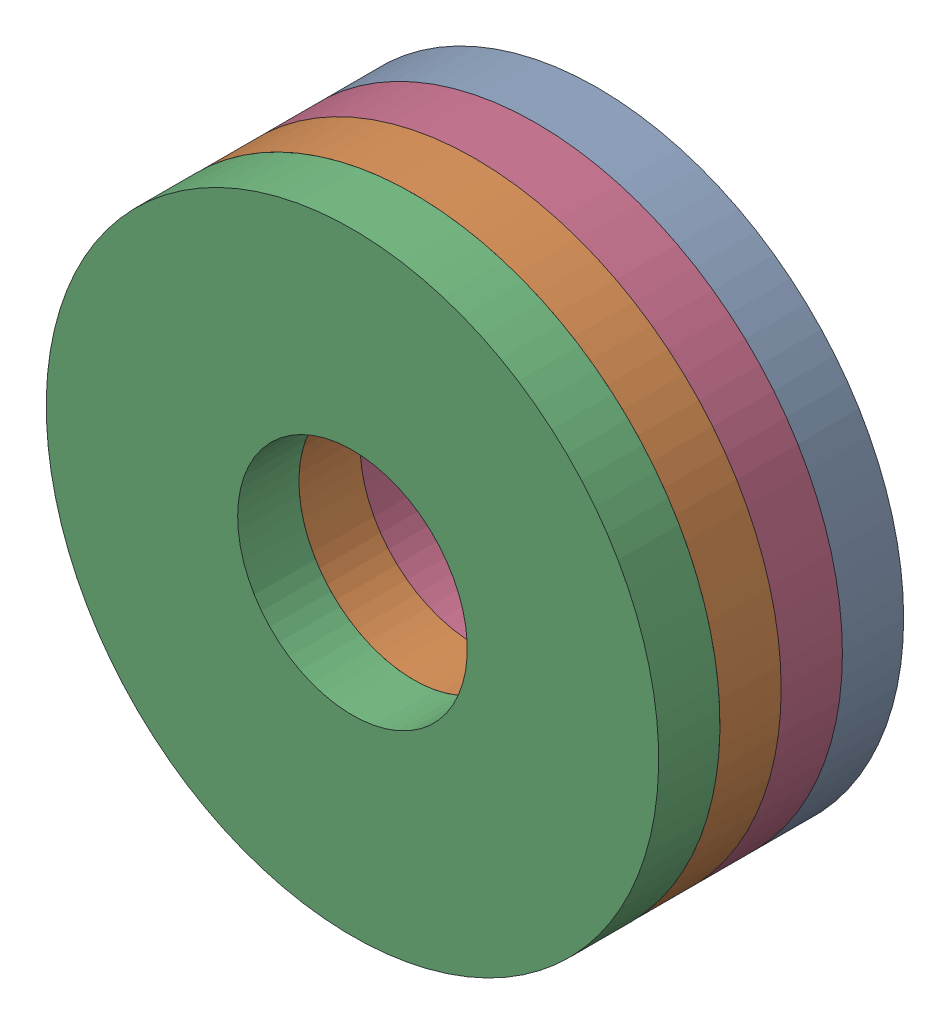
SolidWorks assembly 垫片组, configuration 默认. Lengths in mm.
Overall size (11.19 11.19 3.2).
4 component instances, 1 part files, 3 mates.
Components (placement in the parent):
- 垫片-1: 垫片 [默认] at (0.9786 0.4439 0) size (8 8 0.8)
- 垫片-2: 垫片 [默认] at (0.9786 0.4439 1.6) size (8 8 0.8)
- 垫片-3: 垫片 [默认] at (0.9786 0.4439 2.4) x (0.597023 0.802224 0) z (0 0 1) size (8 8 0.8)
- 垫片-4: 垫片 [默认] at (0.9786 0.4439 0.8) size (8 8 0.8)
Mates (geometry in assembly coordinates):
- 重合3: coincident aligned: circle of 垫片-2; circle of 垫片-4
- 重合4: coincident aligned: circle of 垫片-2; circle of 垫片-3
- 重合5: coincident aligned: circle of 垫片-1; circle of 垫片-4
